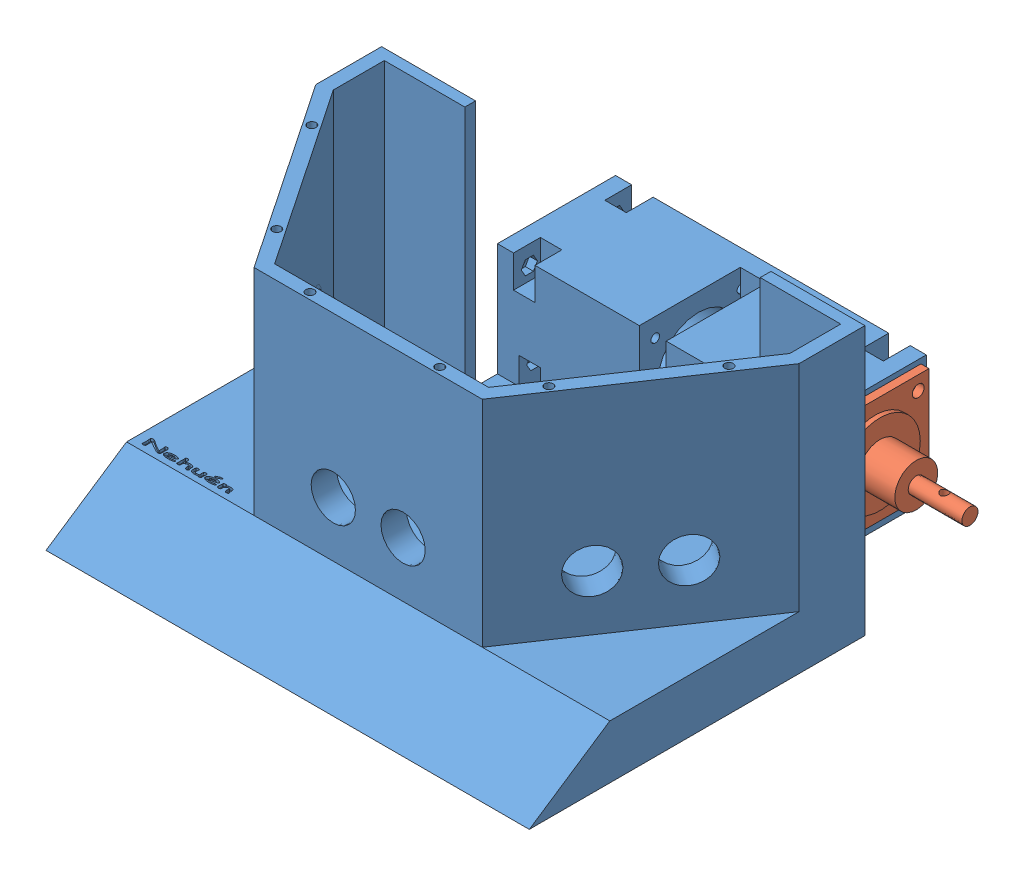
SolidWorks assembly Sumo 2.0, configuration Default. Lengths in mm.
Overall size (186.12 100 180).
2 component instances, 2 part files, 2 mates.
Components (placement in the parent):
- SUMO 3.0-1: SUMO 3.0 [Default] at (-167.7792 66.321 68.3786) size (180 100 180)
- Motor ignis MR06B para sumo.step-2: Motor ignis MR06B para sumo.step [Default] at (-58.5664 44.5455 90.3786) x (0 -0.000305 -1) z (-1 0 0) size (40 40 93)
Mates (geometry in assembly coordinates):
- Coincident2: coincident anti-aligned: plane of SUMO 3.0-1 through (-96.8164 66.4455 68.3786) normal (1 0 0); plane of Motor ignis MR06B para sumo.step-2 through (-96.8164 44.5455 90.3786) normal (-1 0 0)
- Concentric2: concentric anti-aligned: cylinder of SUMO 3.0-1 through (-245.8164 44.5455 90.3786) axis (1 0 0) radius 15.2; cylinder of Motor ignis MR06B para sumo.step-2 through (-96.8164 44.5455 90.3786) axis (-1 0 0) radius 15
